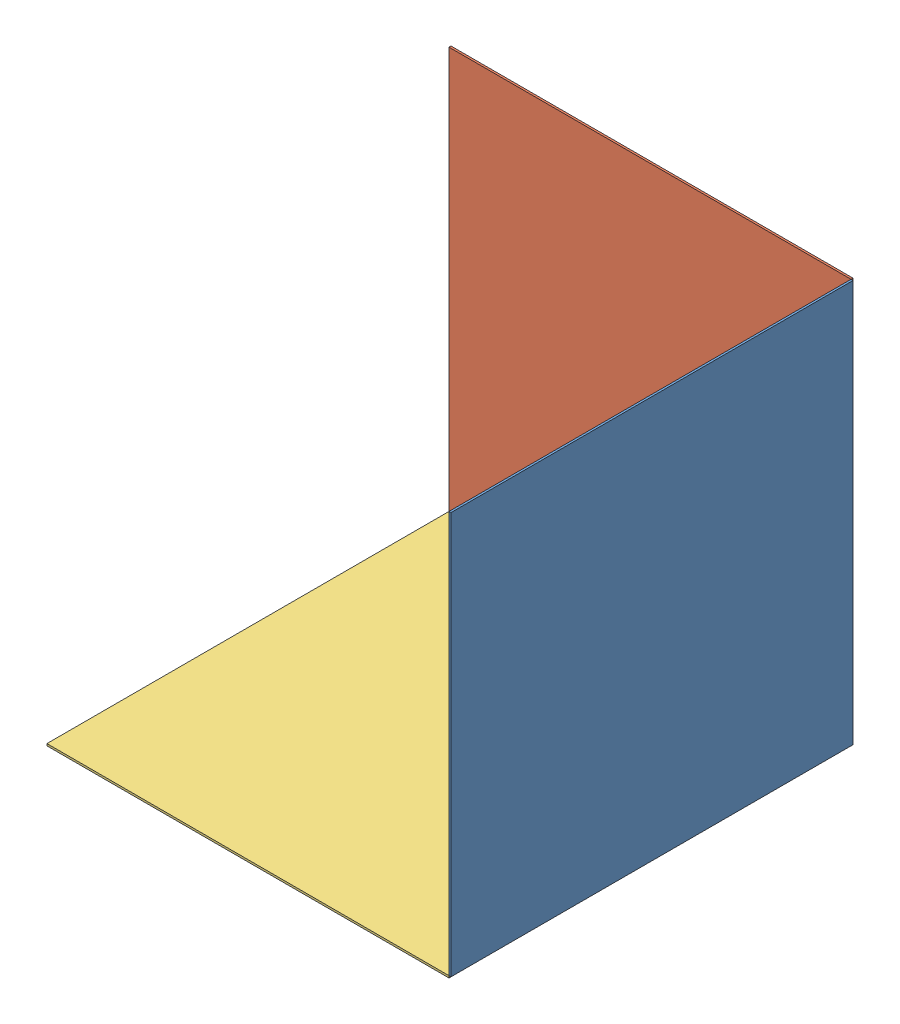
SolidWorks assembly 模型2, configuration 默认. Lengths in mm.
Overall size (201 201 201).
3 component instances, 3 part files, 7 mates.
Components (placement in the parent):
- 侧视图-1: 侧视图 [默认] at (68.6555 1.1657 400.5) size (1 200 200)
- 正视图-1: 正视图 [默认] at (-31.3445 1.1657 299.5) size (200 200 1)
- 俯视图-1: 俯视图 [默认] at (-31.3445 -99.8343 400.5) size (200 1 200)
Mates (geometry in assembly coordinates):
- 重合1: coincident aligned: line of 侧视图-1 through (68.6555 -98.8343 300.5) axis (0 1 0); line of 正视图-1 through (68.6555 -98.8343 300.5) axis (0 1 0)
- 重合2: coincident: point of 侧视图-1; point of 正视图-1
- 重合3: coincident anti-aligned: line of 正视图-1 through (-131.3445 -98.8343 300.5) axis (1 0 0); line of 俯视图-1 through (68.6555 -98.8343 300.5) axis (-1 0 0)
- 重合4: coincident: point of 侧视图-1; point of 俯视图-1
- 重合5: coincident: plane of ? through (-31.3445 -99.4968 400.4978) normal (0 0.999978 0.006625)
- 重合9: coincident: plane of ? through (75.4269 1.1657 400.2705) normal (-0.997705 0 0.067714)
- 重合10: coincident aligned: line of 侧视图-1 through (68.6555 -98.8343 500.5) axis (0 0 -1); line of 俯视图-1 through (68.6555 -98.8343 500.5) axis (0 0 -1)
